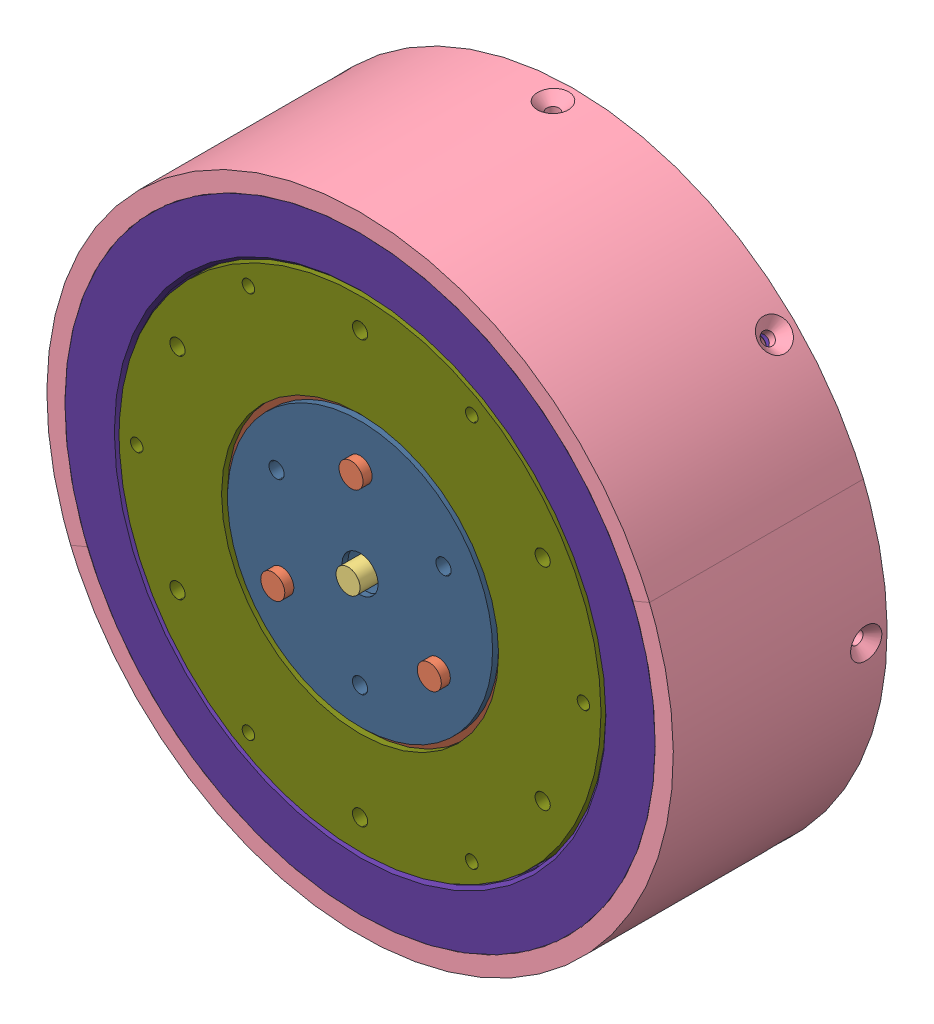
SolidWorks assembly 8108 Gearbox, configuration Default. Lengths in mm.
Overall size (104.9 104.9 46.8).
31 component instances, 22 part files, 0 mates.
Components (placement in the parent):
- 8108 Gearbox.step-1: 8108 Gearbox.step [Default] at origin size (104.9 104.9 46.8)
  - Gearbox.step-1: Gearbox.step [Default] at origin size (104.9 104.9 46.8)
    - Planet Gear (1).step-1: Planet Gear (1).step [Default] at (0 15 4) size (21 21 20)
      - Planet Bearing.step-1: Planet Bearing.step [Default] at origin size (8 8 8)
      - Planet Shaft.step-1: Planet Shaft.step [Default] at (0 0 -11) size (4 4 20)
      - Planet Gear (1)-0.step-1: Planet Gear (1)-0.step [Default] at origin size (21 21 5)
    - Planet Gear (1)_1.step-1: Planet Gear (1)_1.step [Default] at (12.9904 -7.5 4) size (21 21 20)
      - Planet Bearing.step-1: Planet Bearing.step [Default] at origin size (8 8 8)
      - Planet Shaft.step-1: Planet Shaft.step [Default] at (0 0 -11) size (4 4 20)
      - Planet Gear (1)_1-1.step-1: Planet Gear (1)_1-1.step [Default] at origin size (21 21 5)
    - Planet Gear (1)_2.step-1: Planet Gear (1)_2.step [Default] at (-12.9904 -7.5 4) size (21 21 20)
      - Planet Bearing.step-1: Planet Bearing.step [Default] at origin size (8 8 8)
      - Planet Shaft.step-1: Planet Shaft.step [Default] at (0 0 -11) size (4 4 20)
      - Planet Gear (1)_2-2.step-1: Planet Gear (1)_2-2.step [Default] at origin size (21 21 5)
    - Stator.step-1: Stator.step [Default] at origin size (80.75 80.75 11)
    - Internal Gear.step-1: Internal Gear.step [Default] at (0 0 4.5) size (53.5 53.5 5)
    - Planet Input.step-1: Planet Input.step [Default] at (0 0 -2.5) size (40 39.75 15)
    - InputBearing.step-1: InputBearing.step [Default] at (0 0 -1) size (24 24 5)
    - Planet Output.step-1: Planet Output.step [Default] at (0 0 12.5) size (44 44 14.5)
    - OutputBearing.step-1: OutputBearing.step [Default] at (0 0 12.5) size (50 50 6)
    - SunGearHolder.step-1: SunGearHolder.step [Default] at (0 0 -7.5) size (32 32 18.1)
    - Back Housing.step-1: Back Housing.step [Default] at (0 0 -9) size (95.27 94.99 8.3)
    - Rotor Bearing.step-1: Rotor Bearing.step [Default] at (0 0 -10) size (21 21 4)
    - moteus controller.step-1: moteus controller.step [Default] at (0 0 -17.3) x (-1 0 0) z (0 0 -1) size (45 45 9.2)
    - Front Housing Take 2.step-1: Front Housing Take 2.step [Default] at (0 0 12.5) size (80 80 21.5)
    - Outer Housing.step-1: Outer Housing.step [Default] at (0 0 19.5) size (98.01 98.01 35.5)
    - SDP 20tooth spur.step-1: SDP 20tooth spur.step [Default] at (0 0 4.5) size (11 11 12)
    - PositionBoard.step-1: PositionBoard.step [Default] at origin size (56 56 2.97)
    - Controller Cover.step-1: Controller Cover.step [Default] at origin size (61 78.5 8)
    - Shaft.step-1: Shaft.step [Default] at (0 0 -22) size (4 4 24)
    - Reinforcing Ring.step-1: Reinforcing Ring.step [Default] at origin size (104.9 104.9 35.5)
